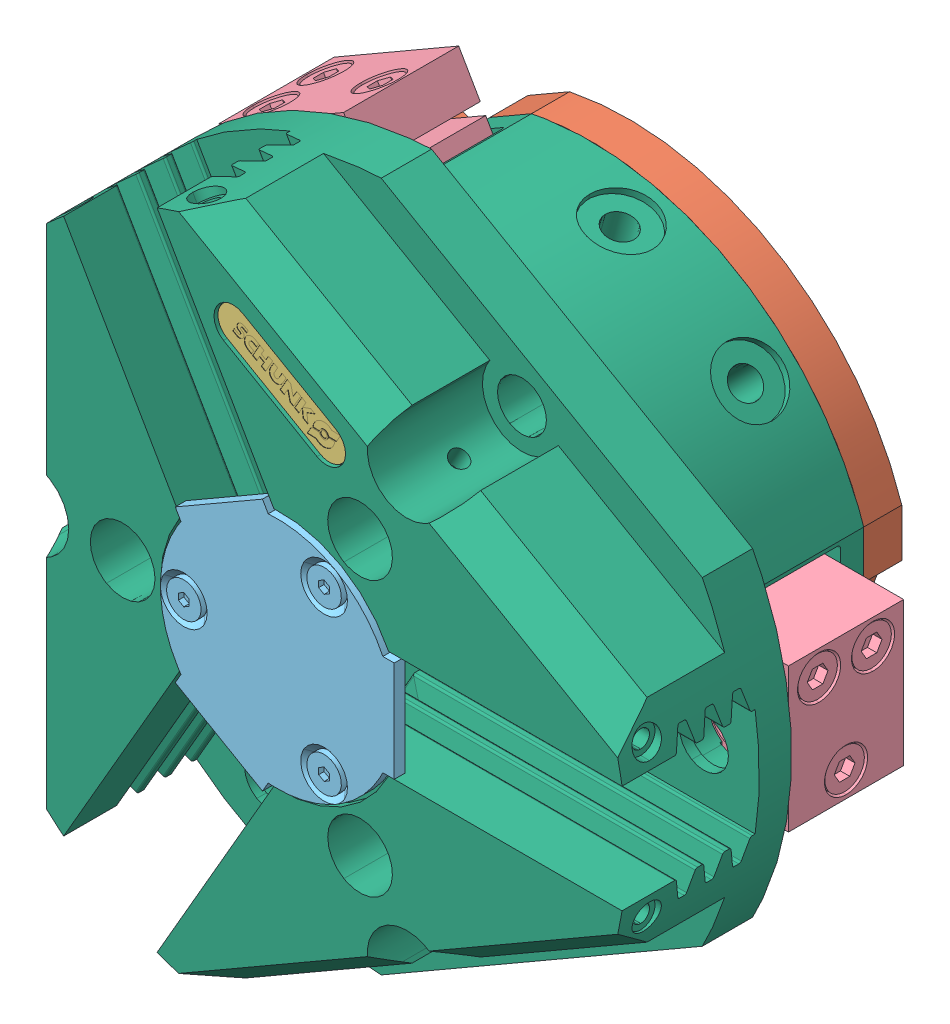
SolidWorks assembly SCHUNK_0303311_PZN_plus_80_1__00000, configuration Default. Lengths in mm.
Overall size (127.31 124.6 48.8).
8 component instances, 6 part files, 0 mates.
Components (placement in the parent):
- SCHUNK_0303311_PZN_plus_80_1__00000_3-1: SCHUNK_0303311_PZN_plus_80_1__00000_3 [Default] at (-28.9242 -13.7533 26.9) x (0.374607 -0.927184 0) z (0 0 -1) size (3.8 2.96 5)
- SCHUNK_0303311_PZN_plus_80_1__00000_9-1: SCHUNK_0303311_PZN_plus_80_1__00000_9 [Default] at (0 0 5.3) x (0.866025 -0.5 0) z (0.5 0.866025 0) size (80 5.3 78)
- SCHUNK_0303311_PZN_plus_80_1__00000_11-1: SCHUNK_0303311_PZN_plus_80_1__00000_11 [Default] at (-0.1613 32.0206 47.6) x (0.866025 -0.5 0) z (0 0 1) size (20 5 0.3)
- SCHUNK_0303311_PZN_plus_80_1__00000_13-1: SCHUNK_0303311_PZN_plus_80_1__00000_13 [Default] at (35 0 8.75) x (1 0 0) z (0 -1 0) size (12 16 20)
- SCHUNK_0303311_PZN_plus_80_1__00000_13-2: SCHUNK_0303311_PZN_plus_80_1__00000_13 [Default] at (-17.5 -30.3109 8.75) x (-0.5 -0.866025 0) z (-0.866025 0.5 0) size (12 16 20)
- SCHUNK_0303311_PZN_plus_80_1__00000_13-3: SCHUNK_0303311_PZN_plus_80_1__00000_13 [Default] at (-17.5 30.3109 8.75) x (-0.5 0.866025 0) z (0.866025 0.5 0) size (12 16 20)
- SCHUNK_0303311_PZN_plus_80_1__00000_17-1: SCHUNK_0303311_PZN_plus_80_1__00000_17 [Default] at (0 0 47.3) x (0.5 0.866025 0) z (0.866025 -0.5 0) size (32.5 1.5 35.15)
- SCHUNK_0303311_PZN_plus_80_1__00000_19-1: SCHUNK_0303311_PZN_plus_80_1__00000_19 [Default] at (0 0 5.3) x (-0.866025 0.5 0) z (0.5 0.866025 0) size (95.91 43 88.5)
